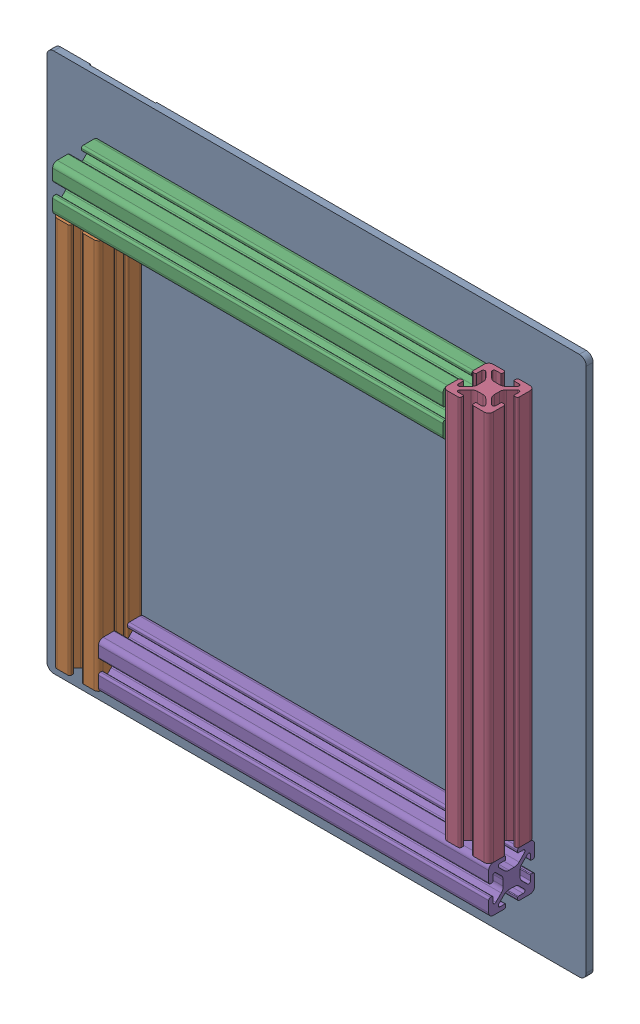
SolidWorks assembly asm_profile_plaque, configuration Défaut. Lengths in mm.
Overall size (235 235 23).
5 component instances, 2 part files, 13 mates.
Components (placement in the parent):
- Hot bed-1: Hot bed [Standard] at (5.4354 -0.165 1.9165) size (235 235 3)
- profile_20_20_m-1: profile_20_20_m [Default] at (-79.5646 -195.165 14.9165) size (20 170 20)
- profile_20_20_m-2: profile_20_20_m [Default] at (-189.5646 84.835 14.9165) x (0 -1 0) z (0 0 1) size (20 170 20)
- profile_20_20_m-3: profile_20_20_m [Default] at (90.4354 194.835 14.9165) x (-1 0 0) z (0 0 1) size (20 170 20)
- profile_20_20_m-6: profile_20_20_m [Default] at (-169.5646 -85.165 14.9165) x (0 1 0) z (0 0 -1) size (20 170 20)
Mates (geometry in assembly coordinates):
- Distance1: distance = 10 mm: line of Hot bed-1 through (-79.5646 -85.165 2.1165) axis (0 0 -1); plane of profile_20_20_m-1 through (-87.5646 -95.165 22.9165) normal (0 -1 0)
- Parallèle1: parallel aligned: plane of Hot bed-1 through (-112.0646 -117.665 4.9165) normal (0 -1 0); plane of profile_20_20_m-1 through (-87.5646 -95.165 22.9165) normal (0 -1 0)
- Coïncidente2: coincident anti-aligned: plane of Hot bed-1 through (5.4354 -0.165 4.9165) normal (0 0 1); plane of profile_20_20_m-1 through (-82.9396 -95.165 4.9165) normal (0 0 -1)
- Largeur1: width: plane of profile_20_20_m-1 through (-89.5646 -95.165 6.9165) normal (-1 0 0); plane of Hot bed-1 through (-69.5646 -95.165 11.5415) normal (1 0 0); line of profile_20_20_m-1 through (-79.5646 -85.165 4.9165) axis (0 0 -1)
- Coïncidente4: coincident aligned: plane of profile_20_20_m-2 through (-89.5646 92.835 22.9165) normal (-1 0 0); plane of profile_20_20_m-1 through (-89.5646 -95.165 18.2915) normal (-1 0 0)
- Coïncidente5: coincident anti-aligned: plane of profile_20_20_m-1 through (-87.5646 74.835 22.9165) normal (0 1 0); plane of profile_20_20_m-2 through (-89.5646 74.835 22.9165) normal (0 -1 0)
- Coïncidente6: coincident anti-aligned: plane of Hot bed-1 through (5.4354 -0.165 4.9165) normal (0 0 1); plane of profile_20_20_m-2 through (-89.5646 88.21 4.9165) normal (0 0 -1)
- Coïncidente7: coincident aligned: plane of profile_20_20_m-2 through (-89.5646 94.835 18.2915) normal (0 1 0); plane of profile_20_20_m-3 through (98.4354 94.835 22.9165) normal (0 1 0)
- Coïncidente8: coincident anti-aligned: plane of profile_20_20_m-2 through (80.4354 92.835 22.9165) normal (1 0 0); plane of profile_20_20_m-3 through (80.4354 94.835 22.9165) normal (-1 0 0)
- Coïncidente9: coincident anti-aligned: plane of Hot bed-1 through (5.4354 -0.165 4.9165) normal (0 0 1); plane of profile_20_20_m-3 through (93.8104 94.835 4.9165) normal (0 0 -1)
- Coïncidente12: coincident anti-aligned: plane of profile_20_20_m-1 through (-69.5646 -95.165 22.9165) normal (1 0 0); plane of profile_20_20_m-6 through (-69.5646 -93.165 51.8243) normal (-1 0 0)
- Coïncidente13: coincident anti-aligned: plane of profile_20_20_m-3 through (98.4354 -75.165 22.9165) normal (0 -1 0); plane of profile_20_20_m-6 through (-69.5646 -75.165 51.8243) normal (0 1 0)
- Coïncidente14: coincident anti-aligned: plane of Hot bed-1 through (5.4354 -0.165 4.9165) normal (0 0 1); plane of profile_20_20_m-6 through (-69.5646 -93.165 49.8243) normal (0 0 -1)
